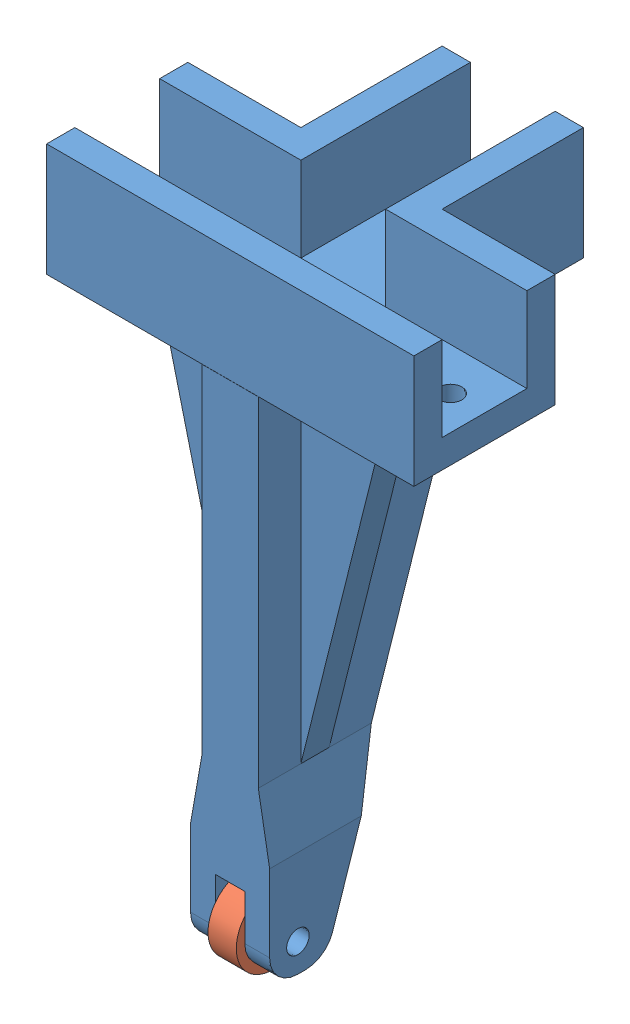
SolidWorks assembly Rise-support, configuration 默认. Lengths in mm.
Overall size (65 131.5 51.53).
2 component instances, 2 part files, 2 mates.
Components (placement in the parent):
- Rise-support-1: Rise-support [默认] at (11.6997 46.6081 145) size (65 130 50.03)
- 4-13-5-Bearing-1: 4-13-5-Bearing [默认] at (1.1101 -38.3919 155.1138) x (0 1 0) z (0 0 1) size (13 5 13)
Mates (geometry in assembly coordinates):
- 重合1: coincident: plane of assembly; plane of assembly; plane of Rise-support-1 through (1.1101 -30.3919 144.2371) normal (-1 0 0); plane of 4-13-5-Bearing-1 through (1.1101 -38.3919 155.1138) normal (1 0 0)
- 同心1: concentric: cylinder of assembly; cylinder of assembly; cylinder of Rise-support-1 through (5.5101 -38.3919 155.1138) axis (-1 0 0) radius 2; cylinder of 4-13-5-Bearing-1 through (-3.8899 -38.3919 155.1138) axis (1 0 0) radius 2
